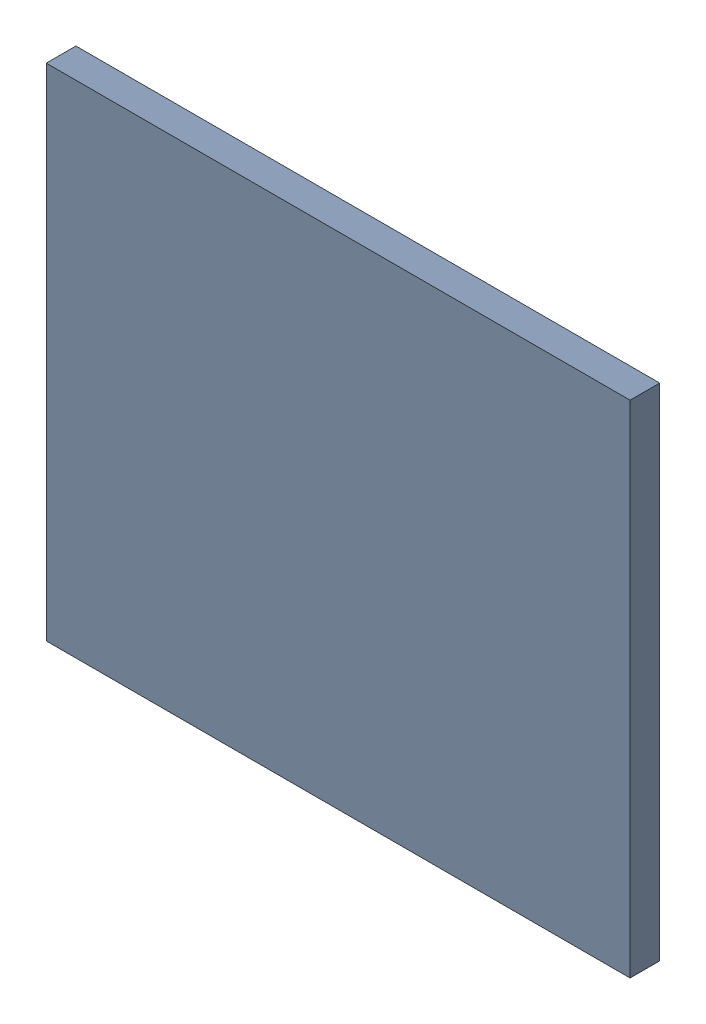
SolidWorks assembly Pad R2-1(31.05mm,40mm) on Top Layer, configuration Predeterminado. Lengths in mm.
Overall size (0.7 0.6 0.04).
2 component instances, 1 part files, 0 mates.
Components (placement in the parent):
- Pad R2-1(31.05mm,40mm) on Top Layer-1-1: Pad R2-1(31.05mm,40mm) on Top Layer-1 [Predeterminado] at (-68.317 -44.187 -0.0457) size (0.7 0.6 0.04)
  - Pad R2-1(31.05mm,40mm) on Top Layer-Part-1-1: Pad R2-1(31.05mm,40mm) on Top Layer-Part-1 [Predeterminado] at origin size (0.7 0.6 0.04)
